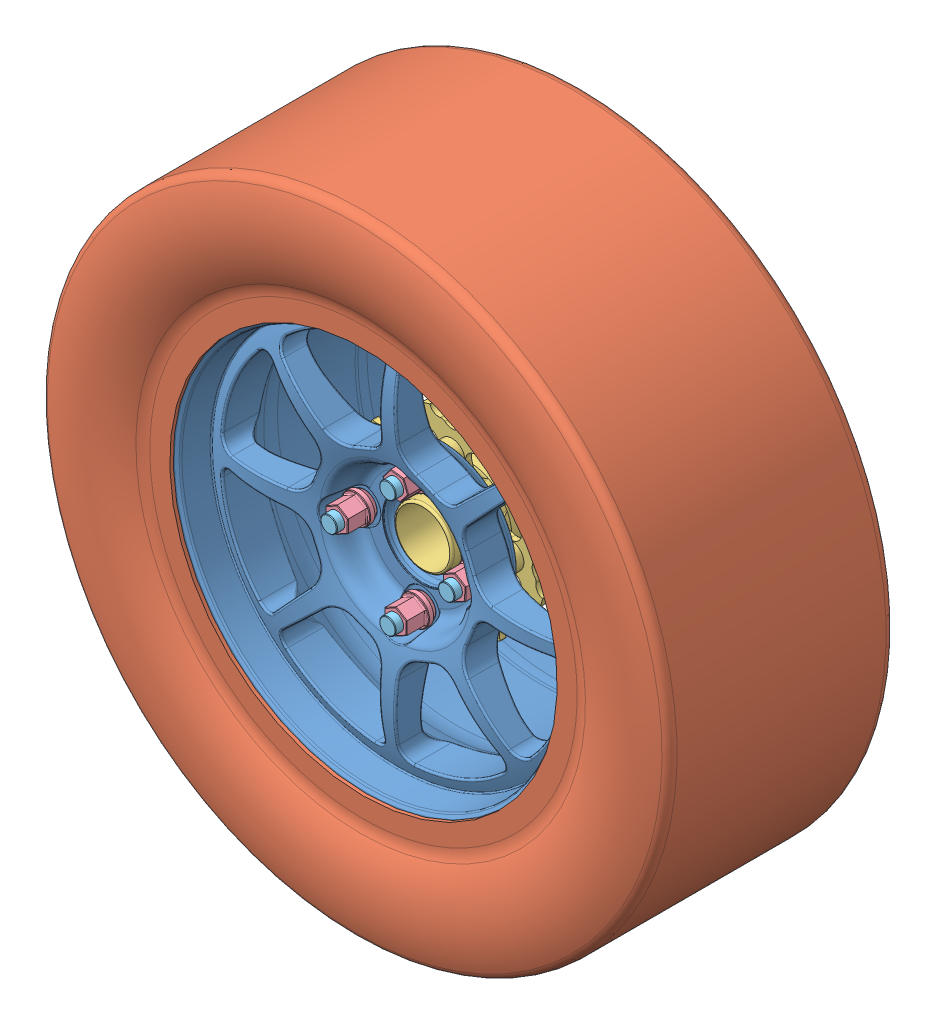
SolidWorks assembly PUTM-S-SF-WT-Hub-Assembly, configuration Default. Lengths in mm.
Overall size (533.4 533.4 204.86).
11 component instances, 5 part files, 18 mates.
Components (placement in the parent):
- PUTM-S-WT-Wheel_Rim-2: PUTM-S-WT-Wheel_Rim [Domyślna] at (14.7172 8.0447 36.3013) x (0 0 -1) z (1 0 0) size (189.8 356.77 356.77)
- PUTM-S-SF-WT-Tire-1: PUTM-S-SF-WT-Tire [Default] at (14.7172 8.0447 14.8013) x (1 0 0) z (0 -1 0) size (533.4 203.2 533.4)
- PUTM-S-SF-WT-Hub-v2-1: PUTM-S-SF-WT-Hub-v2 [Domyślna] at (14.7172 8.0447 53.3013) size (153.82 153.82 128.25)
- PUTM-S-WT-WheelNut-1: PUTM-S-WT-WheelNut [Domyślna] at (64.7172 8.0447 76.5658) x (0.999858 -0.016869 0) z (0.016869 0.999858 0) size (25 27 25)
- PUTM-S-WT-WheelNut-2: PUTM-S-WT-WheelNut [Domyślna] at (14.7172 58.0447 76.5658) x (-0.135726 -0.990746 0) z (0.990746 -0.135726 0) size (25 27 25)
- PUTM-S-WT-WheelNut-3: PUTM-S-WT-WheelNut [Domyślna] at (14.7172 -41.9553 76.5658) x (0.999858 -0.016869 0) z (0.016869 0.999858 0) size (25 27 25)
- PUTM-S-WT-WheelNut-4: PUTM-S-WT-WheelNut [Domyślna] at (-35.2828 8.0447 76.5658) x (0.999858 -0.016869 0) z (0.016869 0.999858 0) size (25 27 25)
- PUTM-S-SF-WT-WH-wheel_stud-1: PUTM-S-SF-WT-WH-wheel_stud [Domyślna] at (14.7172 58.0447 21.3013) x (0 0 1) z (-0.985041 0.172322 0) size (62 20 20)
- PUTM-S-SF-WT-WH-wheel_stud-2: PUTM-S-SF-WT-WH-wheel_stud [Domyślna] at (64.7172 8.0447 21.3013) x (0 0 1) z (-0.985041 0.172322 0) size (62 20 20)
- PUTM-S-SF-WT-WH-wheel_stud-3: PUTM-S-SF-WT-WH-wheel_stud [Domyślna] at (14.7172 -41.9553 21.3013) x (0 0 1) z (-0.985041 0.172322 0) size (62 20 20)
- PUTM-S-SF-WT-WH-wheel_stud-4: PUTM-S-SF-WT-WH-wheel_stud [Domyślna] at (-35.2828 8.0447 21.3013) x (0 0 1) z (-0.985041 0.172322 0) size (62 20 20)
Mates (geometry in assembly coordinates):
- Wspólnie1: coincident anti-aligned: plane of PUTM-S-WT-Wheel_Rim-2 through (-12.7119 8.0447 36.3013) normal (0 0 -1); plane of PUTM-S-SF-WT-Hub-v2-1 through (14.7172 8.0447 36.3013) normal (0 0 1)
- Wspólnie6: coincident anti-aligned: plane of PUTM-S-SF-WT-Hub-v2-1 through (64.7172 8.0447 26.3013) normal (0 0 -1); circle of PUTM-S-WT-WH-wheel_stud-1
- Koncentryczne1: concentric aligned: cylinder of PUTM-S-SF-WT-Hub-v2-1 through (64.7172 8.0447 -74.9487) axis (0 0 1) radius 6; cylinder of PUTM-S-WT-WH-wheel_stud-1 through (64.7172 8.0447 66.3013) axis (0 0 1) radius 6
- Koncentryczne2: concentric anti-aligned: cone of PUTM-S-WT-Wheel_Rim-2 through (14.7172 8.0447 46.8756) axis (0 0 -1); cylinder of PUTM-S-SF-WT-Hub-v2-1 through (14.7172 8.0447 53.3013) axis (0 0 1) radius 25
- Koncentryczne3: concentric anti-aligned: cylinder of PUTM-S-WT-Wheel_Rim-2 through (14.7172 58.0447 101.3404) axis (0 0 -1) radius 7.5; circle of PUTM-S-SF-WT-Hub-v2-1
- Koncentryczne9: concentric aligned: cylinder of PUTM-S-WT-WH-wheel_stud-1 through (64.7172 8.0447 66.3013) axis (0 0 1) radius 6; cylinder of PUTM-S-WT-WheelNut-1 through (64.7172 8.0447 76.5658) axis (0 0 1) radius 6
- Wspólnie8: coincident aligned: circle of PUTM-S-WT-Wheel_Rim-2; cone of PUTM-S-WT-WheelNut-3 through (14.7172 -41.9553 49.5658) axis (0 0 -1)
- Wspólnie9: coincident aligned: circle of PUTM-S-WT-Wheel_Rim-2; cone of PUTM-S-WT-WheelNut-1 through (64.7172 8.0447 49.5658) axis (0 0 -1)
- Wspólnie10: coincident aligned: circle of PUTM-S-WT-Wheel_Rim-2; cone of PUTM-S-WT-WheelNut-2 through (14.7172 58.0447 49.5658) axis (0 0 -1)
- Wspólnie11: coincident aligned: circle of PUTM-S-WT-Wheel_Rim-2; cone of PUTM-S-WT-WheelNut-4 through (-35.2828 8.0447 49.5658) axis (0 0 -1)
- Koncentryczne13: concentric aligned: cylinder of PUTM-S-SF-WT-Hub-v2-1 through (14.7172 58.0447 -74.9487) axis (0 0 1) radius 6; cylinder of PUTM-S-SF-WT-WH-wheel_stud-1 through (14.7172 58.0447 83.3013) axis (0 0 1) radius 7
- Koncentryczne15: concentric aligned: cylinder of PUTM-S-SF-WT-Hub-v2-1 through (-35.2828 8.0447 -74.9487) axis (0 0 1) radius 6; cylinder of PUTM-S-SF-WT-WH-wheel_stud-4 through (-35.2828 8.0447 83.3013) axis (0 0 1) radius 7
- Koncentryczne16: concentric aligned: cylinder of PUTM-S-SF-WT-Hub-v2-1 through (14.7172 -41.9553 -74.9487) axis (0 0 1) radius 6; cylinder of PUTM-S-SF-WT-WH-wheel_stud-3 through (14.7172 -41.9553 83.3013) axis (0 0 1) radius 7
- Koncentryczne17: concentric aligned: cylinder of PUTM-S-SF-WT-Hub-v2-1 through (64.7172 8.0447 -74.9487) axis (0 0 1) radius 6; cylinder of PUTM-S-SF-WT-WH-wheel_stud-2 through (64.7172 8.0447 83.3013) axis (0 0 1) radius 7
- Wspólnie12: coincident anti-aligned: plane of PUTM-S-SF-WT-Hub-v2-1 through (64.7172 8.0447 26.3013) normal (0 0 -1); plane of PUTM-S-SF-WT-WH-wheel_stud-2 through (66.4404 17.8951 26.3013) normal (0 0 1)
- Wspólnie14: coincident anti-aligned: plane of PUTM-S-SF-WT-Hub-v2-1 through (14.7172 58.0447 26.3013) normal (0 0 -1); plane of PUTM-S-SF-WT-WH-wheel_stud-1 through (16.4404 67.8951 26.3013) normal (0 0 1)
- Wspólnie15: coincident anti-aligned: plane of PUTM-S-SF-WT-Hub-v2-1 through (-35.2828 8.0447 26.3013) normal (0 0 -1); plane of PUTM-S-SF-WT-WH-wheel_stud-4 through (-33.5596 17.8951 26.3013) normal (0 0 1)
- Wspólnie16: coincident anti-aligned: plane of PUTM-S-SF-WT-Hub-v2-1 through (14.7172 -41.9553 26.3013) normal (0 0 -1); plane of PUTM-S-SF-WT-WH-wheel_stud-3 through (16.4404 -32.1049 26.3013) normal (0 0 1)
